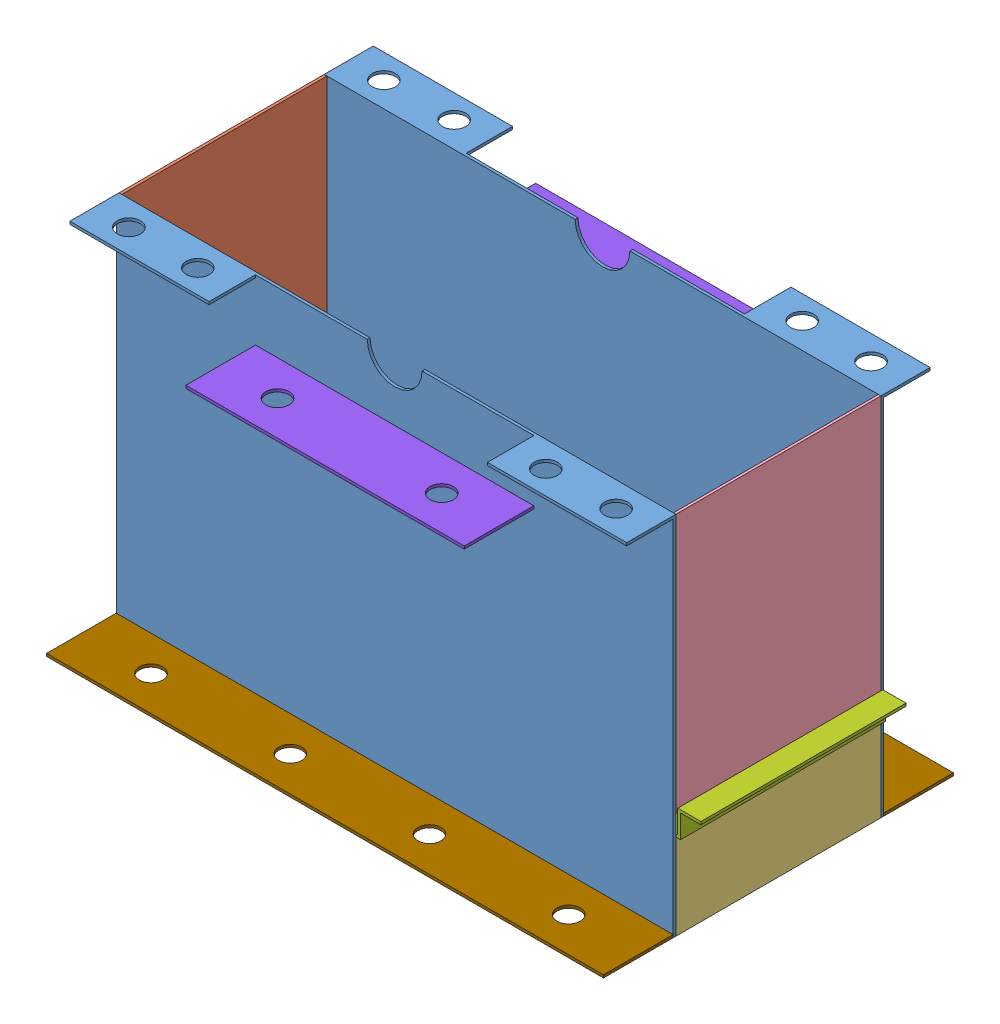
SolidWorks assembly Bottom Assembly, configuration Default. Lengths in mm.
Overall size (318.52 200 191.51).
13 component instances, 9 part files, 36 mates.
Components (placement in the parent):
- Bottom Assembly - Center Casing-1: Bottom Assembly - Center Casing [Default] at (69.4283 125.4695 280.1824) size (304.8 200 26.92)
- Bottom Assembly - Center Casing-2: Bottom Assembly - Center Casing [Default] at (69.4283 125.4695 167.9144) x (-1 0 0) z (0 0 -1) size (304.8 200 26.92)
- Bottom Assembly - Outer Casing-1: Bottom Assembly - Outer Casing [Default] at (-81.4528 25.4695 167.9144) x (0 0 1) z (-1 0 0) size (112.27 200 1.52)
- Bottom Assembly - Outer Casing with slot bottom-1: Bottom Assembly - Outer Casing with slot bottom [Default] at (220.3093 25.4695 280.1824) x (0 0 -1) z (1 0 0) size (112.27 47 1.52)
- Bottom Assembly - Outer Casing with slot top-1: Bottom Assembly - Outer Casing with slot top [Default] at (69.5527 225.4695 167.9144) size (1.39 140.88 112.27)
- Bottom Assembly - Mesh Ledge Long-1: Bottom Assembly - Mesh Ledge Long [Default] at (220.3093 70.9505 273.8324) x (0 0 1) z (-1 0 0) size (6.35 1.52 295.41)
- Bottom Assembly - Mesh Ledge Long-2: Bottom Assembly - Mesh Ledge Long [Default] at (220.3093 70.9505 167.9144) x (0 0 1) z (-1 0 0) size (6.35 1.52 295.41)
- Bottom Assembly - Mesh Ledge Short-1: Bottom Assembly - Mesh Ledge Short [Default] at (-81.4528 72.4695 280.1824) x (1 0 0) z (0 1 0) size (6.35 112.27 1.52)
- Bottom Assembly - Mesh-1: Bottom Assembly - Mesh [Default] at (-81.4528 72.4695 280.1824) size (317 14.22 112.27)
- Bottom Assembly - Bearing Support-1: Bottom Assembly - Bearing Support [Default] at (145.6283 190.6505 128.2954) x (-1 0 0) z (0 0 -1) size (152.4 1.52 38.1)
- Bottom Assembly - Bearing Support-2: Bottom Assembly - Bearing Support [Default] at (-6.7717 190.6505 319.8013) size (152.4 1.52 38.1)
- Bottom Assembly - Supports-1: Bottom Assembly - Supports [Default] at (-82.9717 25.4695 319.8013) size (304.8 1.52 38.1)
- Bottom Assembly - Supports-2: Bottom Assembly - Supports [Default] at (221.8283 25.4695 128.2954) x (-1 0 0) z (0 0 -1) size (304.8 1.52 38.1)
Mates (geometry in assembly coordinates):
- Coincident1: coincident aligned: line of Bottom Assembly - Center Casing-1 through (221.8283 25.4695 280.1824) axis (0 1 0); line of Bottom Assembly - Outer Casing with slot top-1 through (221.8283 84.5884 280.1824) axis (0 1 0)
- Coincident2: coincident aligned: plane of Bottom Assembly - Center Casing-1 through (84.4283 225.4695 281.7013) normal (0 1 0); plane of Bottom Assembly - Outer Casing with slot top-1 through (220.4338 225.4695 280.1824) normal (0 1 0)
- Coincident3: coincident aligned: plane of Bottom Assembly - Center Casing-1 through (221.8283 225.4695 281.7013) normal (1 0 0); plane of Bottom Assembly - Outer Casing with slot top-1 through (221.8283 225.4695 280.1824) normal (1 0 0)
- Coincident4: coincident anti-aligned: line of Bottom Assembly - Center Casing-1 through (221.8283 25.4695 280.1824) axis (0 1 0); line of Bottom Assembly - Outer Casing with slot bottom-1 through (221.8283 72.4695 280.1824) axis (0 -1 0)
- Coincident5: coincident aligned: plane of Bottom Assembly - Center Casing-1 through (221.8283 225.4695 281.7013) normal (1 0 0); plane of Bottom Assembly - Outer Casing with slot bottom-1 through (221.8283 25.4695 280.1824) normal (1 0 0)
- Coincident6: coincident aligned: plane of Bottom Assembly - Center Casing-1 through (-82.9717 25.4695 281.7013) normal (0 -1 0); plane of Bottom Assembly - Outer Casing with slot bottom-1 through (221.8283 25.4695 280.1824) normal (0 -1 0)
- Coincident7: coincident anti-aligned: line of Bottom Assembly - Center Casing-1 through (-82.9717 225.4695 280.1824) axis (0 -1 0); line of Bottom Assembly - Outer Casing-1 through (-82.9717 25.4695 280.1824) axis (0 1 0)
- Coincident8: coincident aligned: plane of Bottom Assembly - Center Casing-1 through (-82.9717 225.4695 281.7013) normal (-1 0 0); plane of Bottom Assembly - Outer Casing-1 through (-82.9717 25.4695 167.9144) normal (-1 0 0)
- Coincident9: coincident aligned: plane of Bottom Assembly - Center Casing-1 through (-82.9717 225.4695 281.7013) normal (0 1 0); plane of Bottom Assembly - Outer Casing-1 through (-82.9717 225.4695 167.9144) normal (0 1 0)
- Coincident11: coincident anti-aligned: line of Bottom Assembly - Center Casing-2 through (221.8283 225.4695 167.9144) axis (0 -1 0); line of Bottom Assembly - Outer Casing with slot top-1 through (221.8283 84.5884 167.9144) axis (0 1 0)
- Coincident12: coincident anti-aligned: line of Bottom Assembly - Center Casing-2 through (-82.9717 25.4695 167.9144) axis (0 1 0); line of Bottom Assembly - Outer Casing-1 through (-82.9717 225.4695 167.9144) axis (0 -1 0)
- Coincident13: coincident aligned: plane of Bottom Assembly - Center Casing-2 through (221.8283 225.4695 166.3954) normal (0 1 0); plane of Bottom Assembly - Outer Casing with slot top-1 through (220.4338 225.4695 280.1824) normal (0 1 0)
- Coincident15: coincident anti-aligned: plane of Bottom Assembly - Center Casing-1 through (69.4283 225.4695 280.1824) normal (0 0 -1); plane of Bottom Assembly - Mesh Ledge Long-1 through (-75.1028 70.9505 280.1824) normal (0 0 1)
- Coincident17: coincident anti-aligned: line of Bottom Assembly - Outer Casing with slot bottom-1 through (220.3093 72.4695 167.9144) axis (0 0 1); line of Bottom Assembly - Mesh Ledge Long-1 through (220.3093 72.4695 280.1824) axis (0 0 -1)
- Coincident18: coincident anti-aligned: plane of Bottom Assembly - Outer Casing with slot bottom-1 through (220.3093 25.4695 280.1824) normal (-1 0 0); plane of Bottom Assembly - Mesh Ledge Long-1 through (220.3093 70.9505 273.8324) normal (1 0 0)
- Coincident19: coincident anti-aligned: plane of Bottom Assembly - Center Casing-2 through (69.4283 225.4695 167.9144) normal (0 0 1); plane of Bottom Assembly - Mesh Ledge Long-2 through (-75.1028 70.9505 167.9144) normal (0 0 -1)
- Coincident20: coincident anti-aligned: line of Bottom Assembly - Outer Casing with slot bottom-1 through (220.3093 72.4695 167.9144) axis (0 0 1); line of Bottom Assembly - Mesh Ledge Long-2 through (220.3093 72.4695 174.2644) axis (0 0 -1)
- Coincident21: coincident anti-aligned: plane of Bottom Assembly - Outer Casing with slot bottom-1 through (220.3093 25.4695 280.1824) normal (-1 0 0); plane of Bottom Assembly - Mesh Ledge Long-2 through (220.3093 70.9505 167.9144) normal (1 0 0)
- Coincident22: coincident anti-aligned: plane of Bottom Assembly - Center Casing-2 through (69.4283 225.4695 167.9144) normal (0 0 1); plane of Bottom Assembly - Mesh Ledge Short-1 through (-81.4528 72.4695 167.9144) normal (0 0 -1)
- Coincident24: coincident anti-aligned: plane of Bottom Assembly - Outer Casing-1 through (-81.4528 25.4695 167.9144) normal (1 0 0); plane of Bottom Assembly - Mesh Ledge Short-1 through (-81.4528 72.4695 167.9144) normal (-1 0 0)
- Coincident25: coincident anti-aligned: line of Bottom Assembly - Mesh Ledge Long-2 through (-75.1028 72.4695 174.2644) axis (0 0 -1); line of Bottom Assembly - Mesh Ledge Short-1 through (-75.1028 72.4695 167.9144) axis (0 0 1)
- Coincident26: coincident anti-aligned: plane of Bottom Assembly - Center Casing-1 through (69.4283 225.4695 280.1824) normal (0 0 -1); plane of Bottom Assembly - Mesh-1 through (-81.4528 73.9884 280.1824) normal (0 0 1)
- Coincident27: coincident anti-aligned: plane of Bottom Assembly - Outer Casing-1 through (-81.4528 25.4695 167.9144) normal (1 0 0); plane of Bottom Assembly - Mesh-1 through (-81.4528 73.9884 280.1824) normal (-1 0 0)
- Coincident28: coincident anti-aligned: plane of Bottom Assembly - Mesh Ledge Long-1 through (-75.1028 72.4695 273.8324) normal (0 1 0); plane of Bottom Assembly - Mesh-1 through (-81.4528 72.4695 280.1824) normal (0 -1 0)
- Coincident29: coincident anti-aligned: plane of Bottom Assembly - Center Casing-1 through (69.4283 225.4695 281.7013) normal (0 0 1); plane of Bottom Assembly - Bearing Support-2 through (145.6283 190.6505 281.7013) normal (0 0 -1)
- Coincident30: coincident anti-aligned: plane of Bottom Assembly - Center Casing-2 through (69.4283 225.4695 166.3954) normal (0 0 -1); plane of Bottom Assembly - Bearing Support-1 through (-6.7717 190.6505 166.3954) normal (0 0 1)
- Coincident31: coincident: point of assembly; point of Bottom Assembly - Center Casing-1; moEndPointRef_w of Bottom Assembly - Bearing Support-2
- Parallel2: parallel anti-aligned: line of Bottom Assembly - Center Casing-1 through (-14.2717 225.4695 281.7013) axis (1 0 0); line of Bottom Assembly - Bearing Support-2 through (145.6283 192.1695 281.7013) axis (-1 0 0)
- Coincident33: coincident: point of assembly; point of Bottom Assembly - Center Casing-2; moEndPointRef_w of Bottom Assembly - Bearing Support-1
- Parallel3: parallel anti-aligned: line of Bottom Assembly - Center Casing-2 through (153.1283 225.4695 166.3954) axis (-1 0 0); line of Bottom Assembly - Bearing Support-1 through (-6.7717 192.1695 166.3954) axis (1 0 0)
- Coincident35: coincident anti-aligned: plane of Bottom Assembly - Center Casing-2 through (69.4283 225.4695 166.3954) normal (0 0 -1); plane of Bottom Assembly - Supports-2 through (-82.9717 25.4695 166.3954) normal (0 0 1)
- Coincident36: coincident anti-aligned: plane of Bottom Assembly - Center Casing-1 through (69.4283 225.4695 281.7013) normal (0 0 1); plane of Bottom Assembly - Supports-1 through (221.8283 25.4695 281.7013) normal (0 0 -1)
- Coincident37: coincident anti-aligned: line of Bottom Assembly - Center Casing-1 through (-82.9717 25.4695 281.7013) axis (1 0 0); line of Bottom Assembly - Supports-1 through (221.8283 25.4695 281.7013) axis (-1 0 0)
- Coincident38: coincident anti-aligned: line of Bottom Assembly - Center Casing-1 through (-82.9717 223.9505 281.7013) axis (0 -1 0); line of Bottom Assembly - Supports-1 through (-82.9717 25.4695 281.7013) axis (0 1 0)
- Coincident39: coincident anti-aligned: line of Bottom Assembly - Center Casing-2 through (221.8283 25.4695 166.3954) axis (-1 0 0); line of Bottom Assembly - Supports-2 through (-82.9717 25.4695 166.3954) axis (1 0 0)
- Coincident40: coincident aligned: line of Bottom Assembly - Center Casing-2 through (-82.9717 25.4695 166.3954) axis (0 1 0); line of Bottom Assembly - Supports-2 through (-82.9717 25.4695 166.3954) axis (0 1 0)
